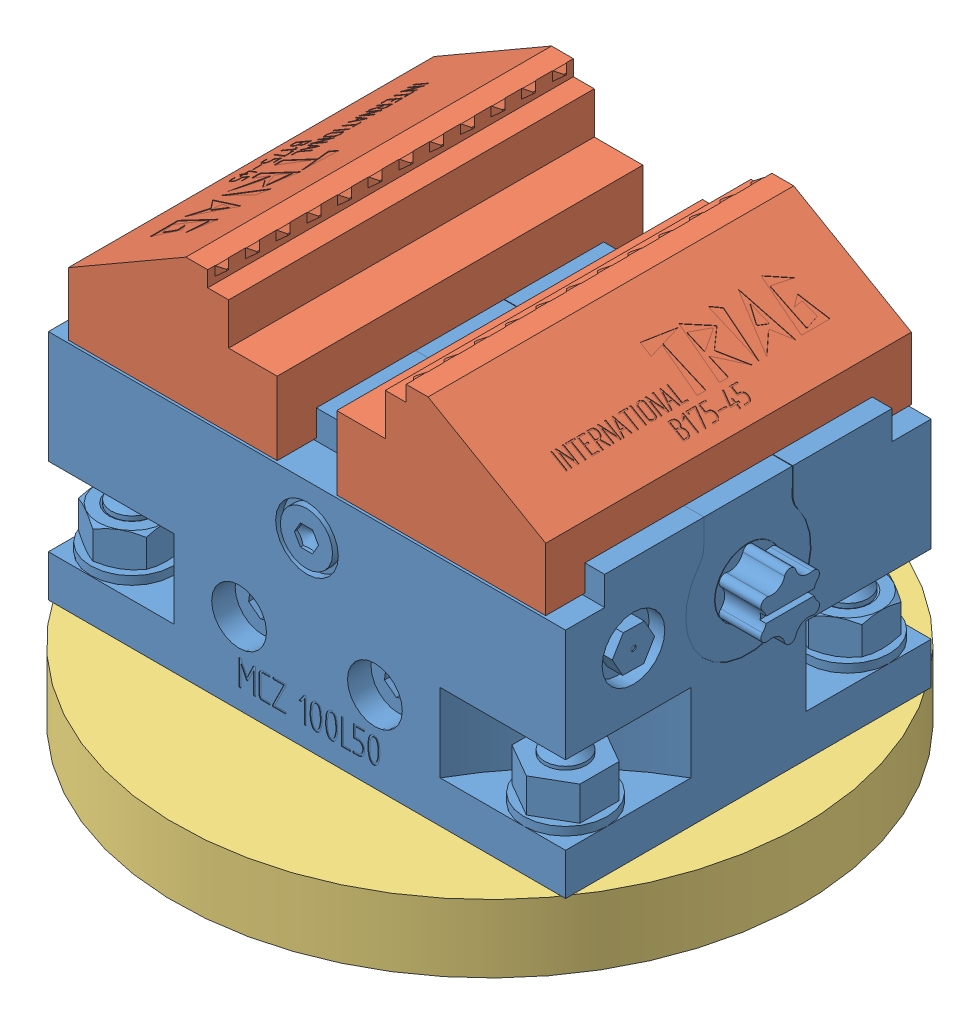
SolidWorks assembly ETAU 25-45mm, configuration Défaut. Lengths in mm.
Overall size (120 83 120).
4 component instances, 3 part files, 11 mates.
Components (placement in the parent):
- Copie de MCZ 100L50_KS^ETAU 25-45mm-1: Copie de MCZ 100L50_KS^ETAU 25-45mm [Défaut] at (0 0 30) size (107 62 70.1) (virtual)
- Copie de B175-45_KS^ETAU 25-45mm-1: Copie de B175-45_KS^ETAU 25-45mm [Défaut] at (37.95 43.436 0) x (0 0 -1) z (0 1 0) size (70 40 25) (virtual)
- Copie de B175-45_KS^ETAU 25-45mm-2: Copie de B175-45_KS^ETAU 25-45mm [Défaut] at (-37.95 43.436 0) x (0 0 1) z (0 1 0) size (70 40 25) (virtual)
- Copie de BASE ADAPT^ETAU 25-45mm-1: Copie de BASE ADAPT^ETAU 25-45mm [Défaut] at (0 -24.064 0) x (1 0 0) z (0 -1 0) size (120 120 13) (virtual)
Mates (geometry in assembly coordinates):
- Coïncidente1: coincident aligned: plane of Copie de MCZ 100L50_KS^ETAU 25-45mm-1 through (0 0 30) normal (1 0 0); plane of assembly through (0 0 0) normal (1 0 0)
- Coïncidente3: coincident aligned: plane of Copie de MCZ 100L50_KS^ETAU 25-45mm-1 through (0 0 0) normal (0 0 1); plane of assembly through (0 0 0) normal (0 0 1)
- Coïncidente4: coincident aligned: plane of Copie de MCZ 100L50_KS^ETAU 25-45mm-1 through (0 0 30) normal (0 1 0); plane of assembly through (0 0 0) normal (0 1 0)
- Coïncidente5: coincident anti-aligned: plane of Copie de B175-45_KS^ETAU 25-45mm-1 through (37.95 43.436 0) normal (0 0 -1); plane of assembly through (0 0 0) normal (0 0 1)
- Coïncidente6: coincident aligned: plane of Copie de B175-45_KS^ETAU 25-45mm-2 through (-37.95 43.436 0) normal (0 0 1); plane of assembly through (0 0 0) normal (0 0 1)
- Coïncidente7: coincident anti-aligned: plane of Copie de MCZ 100L50_KS^ETAU 25-45mm-1 through (49 25.936 0) normal (0 1 0); plane of Copie de B175-45_KS^ETAU 25-45mm-1 through (47.7 25.936 -30.25) normal (0 -1 0)
- Coïncidente9: coincident anti-aligned: plane of Copie de MCZ 100L50_KS^ETAU 25-45mm-1 through (49 25.936 0) normal (0 1 0); plane of Copie de B175-45_KS^ETAU 25-45mm-2 through (-47.7 25.936 30.25) normal (0 -1 0)
- Symétrique1: symmetric aligned: plane of Copie de MCZ 100L50_KS^ETAU 25-45mm-1 through (0 0 30) normal (1 0 0); plane of Copie de B175-45_KS^ETAU 25-45mm-2 through (-15 43.086 -38.5) normal (1 0 0); plane of Copie de B175-45_KS^ETAU 25-45mm-1 through (15 43.086 38.5) normal (-1 0 0)
- Distance1: distance = 38 mm anti-aligned: plane of Copie de B175-45_KS^ETAU 25-45mm-1 through (19 46.086 38.5) normal (-1 0 0); plane of Copie de B175-45_KS^ETAU 25-45mm-2 through (-19 46.086 -38.5) normal (1 0 0)
- Coïncidente10: coincident anti-aligned: plane of Copie de MCZ 100L50_KS^ETAU 25-45mm-1 through (10 -24.064 0) normal (0 -1 0); plane of Copie de BASE ADAPT^ETAU 25-45mm-1 through (0 -24.064 0) normal (0 1 0)
- Coaxiale1: concentric anti-aligned: cylinder of Copie de MCZ 100L50_KS^ETAU 25-45mm-1 through (0 -22.064 0) axis (0 -1 0) radius 11.7378; cylinder of Copie de BASE ADAPT^ETAU 25-45mm-1 through (0 -37.064 0) axis (0 1 0) radius 60
